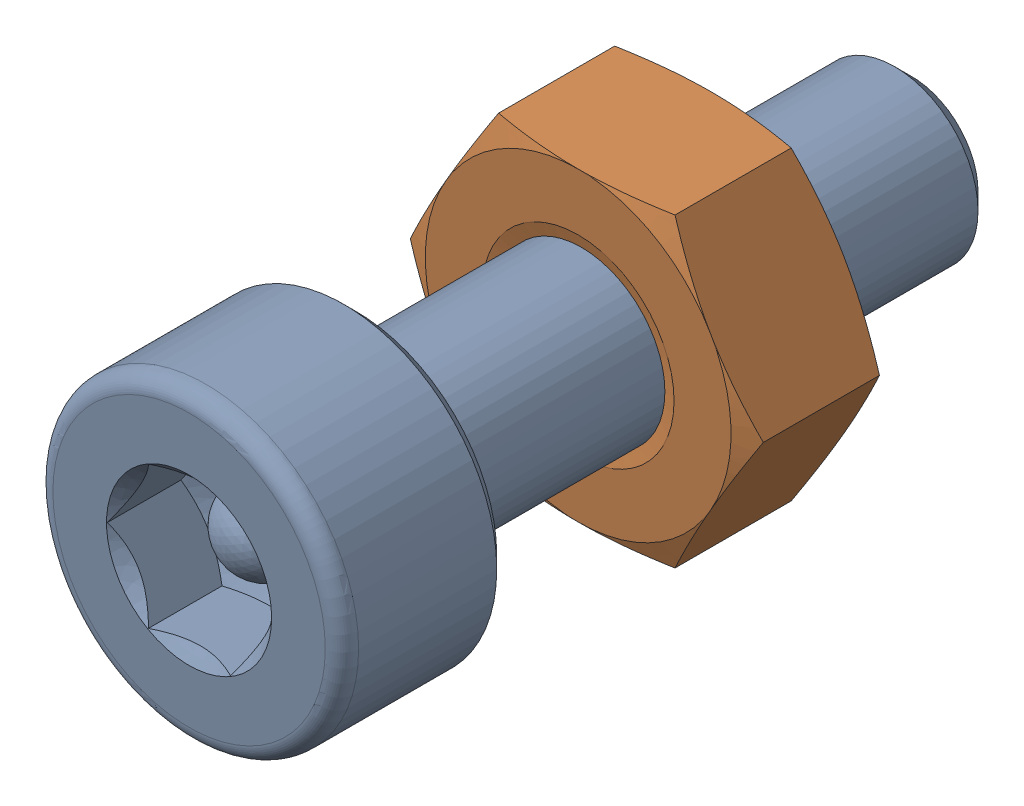
SolidWorks assembly Screw and Nut M3x010_017, configuration Varsayılan. Lengths in mm.
Overall size (6.35 5.5 13.14).
2 component instances, 2 part files, 0 mates.
Components (placement in the parent):
- M3x10-Screw016-1: M3x10-Screw016 [Varsayılan] at origin size (5.5 5.5 13.14)
- M3-Nut048-1: M3-Nut048 [Varsayılan] at (0 0 -4) x (-1 0 0) z (0 0 -1) size (6.35 5.5 2.4)
